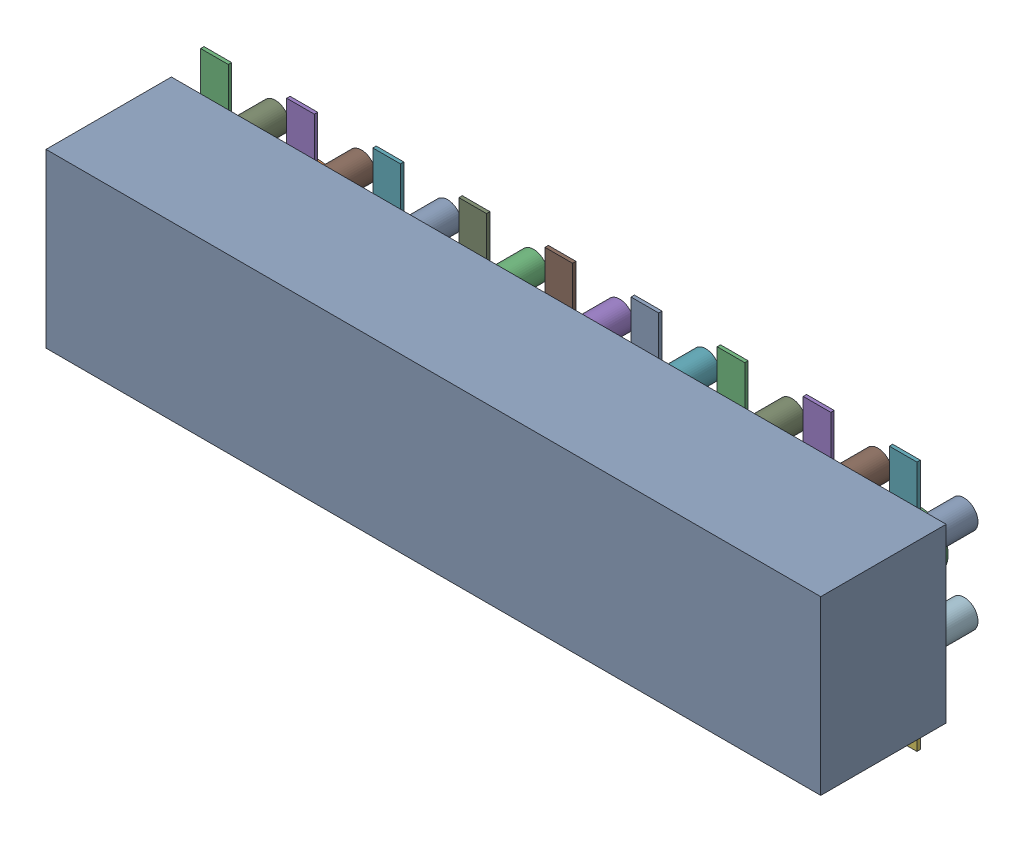
SolidWorks assembly Body_1, configuration Predeterminado. Lengths in mm.
Overall size (22.86 7.4 5.5).
41 component instances, 39 part files, 0 mates.
Components (placement in the parent):
- =_[0_1_1_2]-1: =_[0_1_1_2] [Predeterminado] at (0 0 0.1) size (22.86 5.08 3.7)
- =_[0_1_1_3]-1: =_[0_1_1_3] [Predeterminado] at origin size (21.14 7.4 0.1)
  - SOLID-1: SOLID [Predeterminado] at origin size (0.82 1.58 0.1)
  - SOLID_2-1: SOLID_2 [Predeterminado] at origin size (0.82 1.58 0.1)
  - SOLID_3-1: SOLID_3 [Predeterminado] at origin size (0.82 1.58 0.1)
  - SOLID_4-1: SOLID_4 [Predeterminado] at origin size (0.82 1.58 0.1)
  - SOLID_5-1: SOLID_5 [Predeterminado] at origin size (0.82 1.58 0.1)
  - SOLID_6-1: SOLID_6 [Predeterminado] at origin size (0.82 1.58 0.1)
  - SOLID_7-1: SOLID_7 [Predeterminado] at origin size (0.82 1.58 0.1)
  - SOLID_8-1: SOLID_8 [Predeterminado] at origin size (0.82 1.58 0.1)
  - SOLID_9-1: SOLID_9 [Predeterminado] at origin size (0.82 1.58 0.1)
  - SOLID_10-1: SOLID_10 [Predeterminado] at origin size (0.82 1.58 0.1)
  - SOLID_11-1: SOLID_11 [Predeterminado] at origin size (0.82 1.58 0.1)
  - SOLID_12-1: SOLID_12 [Predeterminado] at origin size (0.82 1.58 0.1)
  - SOLID_13-1: SOLID_13 [Predeterminado] at origin size (0.82 1.58 0.1)
  - SOLID_14-1: SOLID_14 [Predeterminado] at origin size (0.82 1.58 0.1)
  - SOLID_15-1: SOLID_15 [Predeterminado] at origin size (0.82 1.58 0.1)
  - SOLID_16-1: SOLID_16 [Predeterminado] at origin size (0.82 1.58 0.1)
  - SOLID_17-1: SOLID_17 [Predeterminado] at origin size (0.82 1.58 0.1)
  - SOLID_18-1: SOLID_18 [Predeterminado] at origin size (0.82 1.58 0.1)
- =_[0_1_1_4]-1: =_[0_1_1_4] [Predeterminado] at origin size (21.14 3.36 1.8)
  - SOLID_19-1: SOLID_19 [Predeterminado] at origin size (0.82 0.82 1.8)
  - SOLID_20-1: SOLID_20 [Predeterminado] at origin size (0.82 0.82 1.8)
  - SOLID_21-1: SOLID_21 [Predeterminado] at origin size (0.82 0.82 1.8)
  - SOLID_22-1: SOLID_22 [Predeterminado] at origin size (0.82 0.82 1.8)
  - SOLID_23-1: SOLID_23 [Predeterminado] at origin size (0.82 0.82 1.8)
  - SOLID_24-1: SOLID_24 [Predeterminado] at origin size (0.82 0.82 1.8)
  - SOLID_25-1: SOLID_25 [Predeterminado] at origin size (0.82 0.82 1.8)
  - SOLID_26-1: SOLID_26 [Predeterminado] at origin size (0.82 0.82 1.8)
  - SOLID_27-1: SOLID_27 [Predeterminado] at origin size (0.82 0.82 1.8)
  - SOLID_28-1: SOLID_28 [Predeterminado] at origin size (0.82 0.82 1.8)
  - SOLID_29-1: SOLID_29 [Predeterminado] at origin size (0.82 0.82 1.8)
  - SOLID_30-1: SOLID_30 [Predeterminado] at origin size (0.82 0.82 1.8)
  - SOLID_31-1: SOLID_31 [Predeterminado] at origin size (0.82 0.82 1.8)
  - SOLID_32-1: SOLID_32 [Predeterminado] at origin size (0.82 0.82 1.8)
  - SOLID_33-1: SOLID_33 [Predeterminado] at origin size (0.82 0.82 1.8)
  - SOLID_34-1: SOLID_34 [Predeterminado] at origin size (0.82 0.82 1.8)
  - SOLID_35-1: SOLID_35 [Predeterminado] at origin size (0.82 0.82 1.8)
  - SOLID_36-1: SOLID_36 [Predeterminado] at origin size (0.82 0.82 1.8)
  - SOLID_37-1: SOLID_37 [Predeterminado] at origin size (1.6 1.6 1.8)
  - SOLID_38-1: SOLID_38 [Predeterminado] at origin size (1.6 1.6 1.8)
